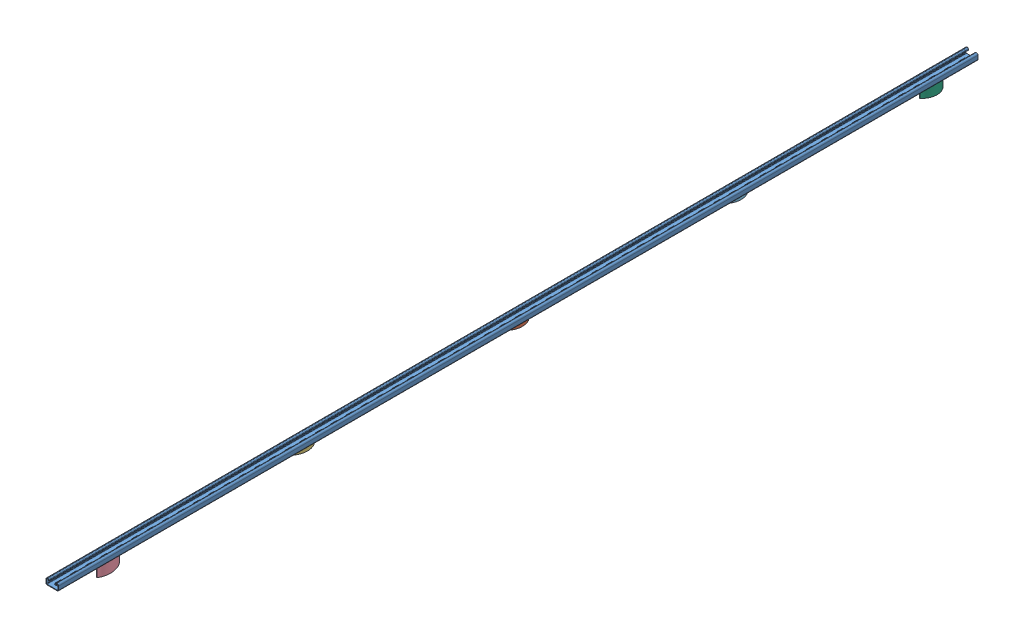
SolidWorks assembly Roof Rack Strut, configuration Default. Lengths in mm.
Overall size (41.28 67.43 3048).
6 component instances, 6 part files, 10 mates.
Components (placement in the parent):
- 3310T8_Strut Channel-1: 3310T8_Strut Channel [3310T8] at (-622.3 1893.0006 957.7806) x (0 -1 0) z (0 0 1) size (20.64 41.27 3048)
- Center Spacer V1-1: Center Spacer V1 [Default] at (-622.3 1880.3006 -584.4756) size (31.75 16.33 76.2)
- Front Center Spacer V1-1: Front Center Spacer V1 [Default] at (-622.3 1878.7131 126.7244) size (31.75 18.31 76.2)
- Front Spacer V1-1: Front Spacer V1 [Default] at (-622.3 1854.9006 772.8369) size (31.75 46.79 76.2)
- Rear Center Spacer V1-1: Rear Center Spacer V1 [Default] at (-622.3 1881.8881 -1309.9631) size (31.75 14.47 76.2)
- Rear Spacer V1-1: Rear Spacer V1 [Default] at (-622.3 1858.0756 -1956.0756) size (31.75 40.44 76.2)
Mates (geometry in assembly coordinates):
- Coincident2: coincident anti-aligned: plane of 3310T8_Strut Channel-1 through (-605.1232 1893.0006 -2090.2194) normal (0 -1 0); plane of Front Spacer V1-1 through (-638.175 1893.0006 810.9369) normal (0 1 0)
- Coincident3: coincident anti-aligned: plane of 3310T8_Strut Channel-1 through (-605.1232 1893.0006 -2090.2194) normal (0 -1 0); plane of Center Spacer V1-1 through (-638.175 1893.0006 -546.3756) normal (0 1 0)
- Coincident5: coincident anti-aligned: plane of 3310T8_Strut Channel-1 through (-605.1232 1893.0006 -2090.2194) normal (0 -1 0); plane of Front Center Spacer V1-1 through (-638.175 1893.0006 164.8244) normal (0 1 0)
- Coincident6: coincident anti-aligned: plane of 3310T8_Strut Channel-1 through (-605.1232 1893.0006 -2090.2194) normal (0 -1 0); plane of Rear Center Spacer V1-1 through (-638.175 1893.0006 -1271.8631) normal (0 1 0)
- Coincident7: coincident anti-aligned: plane of 3310T8_Strut Channel-1 through (-605.1232 1893.0006 -2090.2194) normal (0 -1 0); plane of Rear Spacer V1-1 through (-638.175 1893.0006 -1917.9756) normal (0 1 0)
- Concentric1: concentric anti-aligned: cylinder of 3310T8_Strut Channel-1 through (-622.3 1895.0326 772.8369) axis (0 -1 0) radius 7.1437; cylinder of Front Spacer V1-1 through (-622.3 1849.2995 772.8369) axis (0 1 0) radius 6.5
- Concentric2: concentric anti-aligned: cylinder of 3310T8_Strut Channel-1 through (-622.3 1895.0326 126.7244) axis (0 -1 0) radius 7.1437; cylinder of Front Center Spacer V1-1 through (-622.3 1877.7861 126.7244) axis (0 1 0) radius 6.5
- Concentric3: concentric anti-aligned: cylinder of 3310T8_Strut Channel-1 through (-622.3 1895.0326 -584.4756) axis (0 -1 0) radius 7.1437; cylinder of Center Spacer V1-1 through (-622.3 1879.7641 -584.4756) axis (0 1 0) radius 6.5
- Concentric4: concentric anti-aligned: cylinder of 3310T8_Strut Channel-1 through (-622.3 1895.0326 -1309.9631) axis (0 -1 0) radius 7.1437; cylinder of Rear Center Spacer V1-1 through (-622.3 1881.6284 -1309.9631) axis (0 1 0) radius 6.5
- Concentric5: concentric anti-aligned: cylinder of 3310T8_Strut Channel-1 through (-622.3 1895.0326 -1956.0756) axis (0 -1 0) radius 7.1437; cylinder of Rear Spacer V1-1 through (-622.3 1855.6512 -1956.0756) axis (0 1 0) radius 6.5
